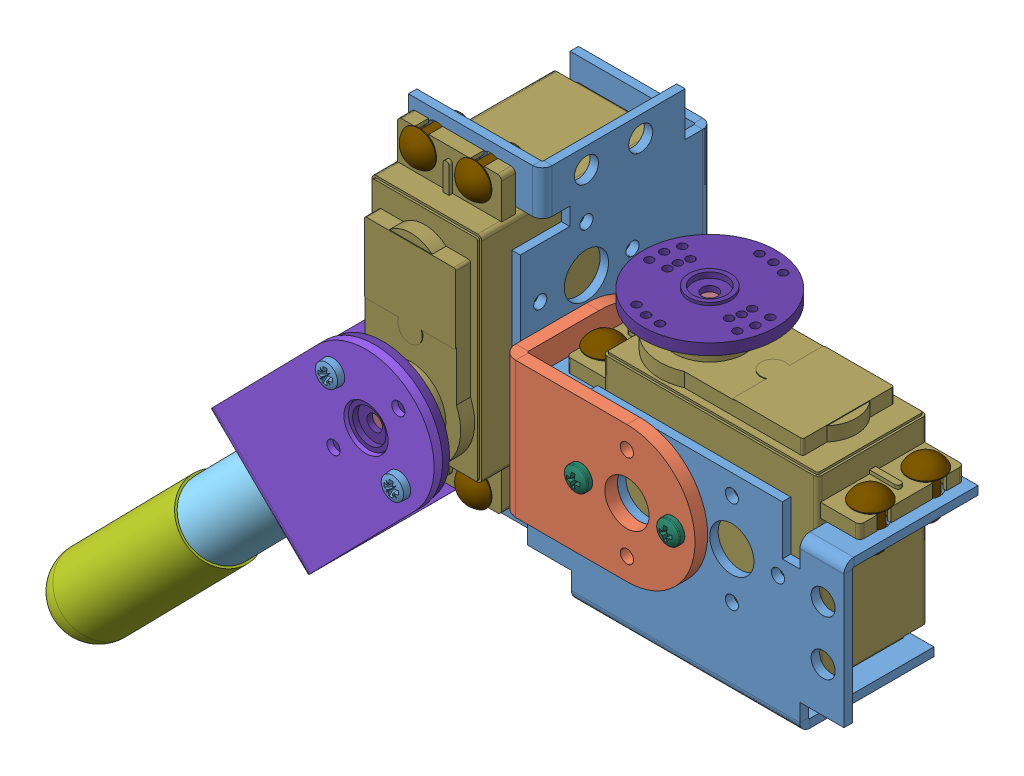
SolidWorks assembly 2DOFA, configuration Default. Lengths in mm.
Overall size (157.72 123.87 57.33).
51 component instances, 19 part files, 82 mates.
Components (placement in the parent):
- asb-04-1: asb-04 [Default] at (0 17.3609 0) x (-1 0 0) z (0 -1 0) size (57.15 24.21 34.72)
- asb-06-1: asb-06 [Default] at (-30.9626 22.7838 2.286) x (-1 0 0) z (0 -1 0) size (34.92 27.61 24.59)
- asb-04-2: asb-04 [Default] at (-30.9626 31.115 -18.4531) x (0 -1 0) z (0 0 -1) size (57.15 24.21 34.72)
- Nut Hex 2-56 (SN-02)-1: Nut Hex 2-56 (SN-02) [Default] at (-16.6624 22.7838 -3.2004) x (0.923728 0.383049 0) z (0 0 -1) size (4.78 5.51 1.68)
- Nut Hex 2-56 (SN-02)-2: Nut Hex 2-56 (SN-02) [Default] at (0 22.7838 -3.2004) x (0.923728 0.383049 0) z (0 0 -1) size (4.78 5.51 1.68)
- BB-03-1: BB-03 [Default] at (-7.842 -10.251 -1.0597) x (0 1 0) z (-0.297391 0 0.954756) size (4 9.5 9.5) (hidden)
- Nut Hex M3-1: Nut Hex M3 [Default] at (-9.9314 4.424 -14.2748) x (1 0 0) z (0 1 0) size (5.5 6.35 2.9)
- at-02-1: at-02 [Default] at (-66.3584 -0.3496 -13.6275) x (-0.713907 0.700241 0) z (-0.700241 -0.713907 0) size (12.7 12.7 76.2)
- 4-40 x 0.250 SHCS (SHS-01)-1: 4-40 x 0.250 SHCS (SHS-01) [Default] at (-73.0282 -7.1496 -22.8223) x (0 0 1) z (0.827472 -0.561508 0) size (9.19 4.65 4.65)
- REC-06-1: REC-06 [Default] at (-97.662 -32.2641 -13.6275) x (-0.713907 0.700241 0) z (0 0 1) size (13.46 38.1 13.46)
- asb-09-1: asb-09 [Default] at (-65.2468 0.7837 -13.6275) x (0 0 1) z (-0.713907 0.700241 0) size (52.25 40.87 24.61)
- BB-03-2: BB-03 [Default] at (-45.2374 21.1836 -40.6014) x (0 0 -1) z (0.990627 0.136598 0) size (4 9.5 9.5)
- hub-08-1: hub-08 [Default] at (-64.1352 1.917 -13.6275) x (0 0 1) z (0.713907 -0.700241 0) size (23.8 16.66 23.8)
- Washer Lock M3-1: Washer Lock M3 [Default] at (-45.2374 21.1836 -36.6014) x (0 0 -1) z (1 0 0) size (0.79 5.99 5.99)
- Nut Hex 2-56 (SN-02)-3: Nut Hex 2-56 (SN-02) [Default] at (-45.2374 21.1836 -32.6136) size (4.78 5.51 1.68)
- Nut Hex 2-56 (SN-02)-4: Nut Hex 2-56 (SN-02) [Default] at (-63.0057 3.0685 -21.9587) x (0.035595 -0.034914 -0.998756) z (0.700241 0.713907 0) size (4.78 5.51 1.68)
- Nut Hex 2-56 (SN-02)-5: Nut Hex 2-56 (SN-02) [Default] at (-63.0057 3.0685 -5.2963) x (0.035595 -0.034914 -0.998756) z (0.700241 0.713907 0) size (4.78 5.51 1.68)
- Servo_complete-1: Servo_complete [Default] at (0.0686 29.058 -14.2748) x (-1 0 0) z (0 0 -1) size (53 41.78 19.8)
  - Servo_case-1: Servo_case [Default] at origin size (53 38.29 19.8)
  - Output_shaft-1: Output_shaft [Default] at (10 3.0362 0) size (5.71 7.87 5.71)
  - Binding Head Screw_AI-1: Binding Head Screw_AI [CR-BHMS 0.06-80x0.625x0.625-S] at (-17.241 -25.1288 7.741) x (0 1 0) z (0 0 1) size (31.27 3.2 3.2)
  - Binding Head Screw_AI-2: Binding Head Screw_AI [CR-BHMS 0.06-80x0.625x0.625-S] at (-17.241 -25.1288 -7.741) x (0 1 0) z (0 0 1) size (31.27 3.2 3.2)
  - Binding Head Screw_AI-3: Binding Head Screw_AI [CR-BHMS 0.06-80x0.625x0.625-S] at (17.241 -25.1288 7.741) x (0 1 0) z (0 0 1) size (31.27 3.2 3.2)
  - Binding Head Screw_AI-4: Binding Head Screw_AI [CR-BHMS 0.06-80x0.625x0.625-S] at (17.241 -25.1288 -7.741) x (0 1 0) z (0 0 1) size (31.27 3.2 3.2)
- Servo_complete-2: Servo_complete [Default] at (-45.2374 31.1836 -6.756) x (0 -1 0) z (-1 0 0) size (53 41.78 19.8)
  - Servo_case-1: Servo_case [Default] at origin size (53 38.29 19.8)
  - Output_shaft-1: Output_shaft [Default] at (10 3.0362 0) size (5.71 7.87 5.71)
  - Binding Head Screw_AI-1: Binding Head Screw_AI [CR-BHMS 0.06-80x0.625x0.625-S] at (-17.241 -25.1288 7.741) x (0 1 0) z (0 0 1) size (31.27 3.2 3.2)
  - Binding Head Screw_AI-2: Binding Head Screw_AI [CR-BHMS 0.06-80x0.625x0.625-S] at (-17.241 -25.1288 -7.741) x (0 1 0) z (0 0 1) size (31.27 3.2 3.2)
  - Binding Head Screw_AI-3: Binding Head Screw_AI [CR-BHMS 0.06-80x0.625x0.625-S] at (17.241 -25.1288 7.741) x (0 1 0) z (0 0 1) size (31.27 3.2 3.2)
  - Binding Head Screw_AI-4: Binding Head Screw_AI [CR-BHMS 0.06-80x0.625x0.625-S] at (17.241 -25.1288 -7.741) x (0 1 0) z (0 0 1) size (31.27 3.2 3.2)
- 2-56 X 0.250 PHS (PHS-02)-5: 2-56 X 0.250 PHS (PHS-02) [Default] at (-16.6624 22.7838 3.8608) x (0 0 -1) z (1 0 0) size (7.89 4.24 4.24)
- 2-56 X 0.250 PHS (PHS-02)-6: 2-56 X 0.250 PHS (PHS-02) [Default] at (0 22.7838 3.8608) x (0 0 -1) z (1 0 0) size (7.89 4.24 4.24)
- Washer Lock M3-2: Washer Lock M3 [Default] at (-9.9314 0 -14.2748) x (0 1 0) z (0 0 1) size (0.79 5.99 5.99)
- BB-03-3: BB-03 [Default] at (-9.9314 -0.7874 -14.2748) x (0 1 0) z (-0.202028 0 0.97938) size (4 9.5 9.5)
- M3 X 8 LG PHMS (PHS-00)-1: M3 X 8 LG PHMS (PHS-00) [Default] at (-9.9314 -6.9874 -14.2748) x (0 1 0) z (0 0 1) size (10.37 5.6 5.6)
- 2-56 X 0.250 PHS (PHS-02)-7: 2-56 X 0.250 PHS (PHS-02) [Default] at (-67.4612 -1.4739 -21.9587) x (0.700241 0.713907 0) z (0 0 1) size (7.89 4.24 4.24)
- 2-56 X 0.250 PHS (PHS-02)-8: 2-56 X 0.250 PHS (PHS-02) [Default] at (-67.4612 -1.4739 -5.2963) x (0.700241 0.713907 0) z (0 0 1) size (7.89 4.24 4.24)
- M3 X 8 LG PHMS (PHS-00)-2: M3 X 8 LG PHMS (PHS-00) [Default] at (-45.2374 21.1836 -42.8014) x (0 0 1) z (-1 0 0) size (10.37 5.6 5.6)
- ServoHornPlastic-1: ServoHornPlastic [Default] at (-9.9314 47.234 -14.2748) x (0.986558 0 0.163414) z (-0.163414 0 0.986558) size (24 5 24)
- NSRF-01-1: NSRF-01 [Default] at (-23.9314 35.8273 -19.2748) x (0 -1 0) z (0 0 1) size (9.65 6.35 6.35)
- NSRF-01-2: NSRF-01 [Default] at (-23.9314 35.8273 -9.2748) x (0 -1 0) z (0 0 1) size (9.65 6.35 6.35)
- NSRF-01-3: NSRF-01 [Default] at (24.0686 35.8273 -9.2748) x (0 -1 0) z (0 0 1) size (9.65 6.35 6.35)
- NSRF-01-4: NSRF-01 [Default] at (24.0686 35.8273 -19.2748) x (0 -1 0) z (0 0 1) size (9.65 6.35 6.35)
- NSRF-01-6: NSRF-01 [Default] at (-40.2374 55.1836 0.0133) x (0 0 -1) z (1 0 0) size (9.65 6.35 6.35)
- NSRF-01-7: NSRF-01 [Default] at (-50.2374 55.1836 0.0133) x (0 0 -1) z (1 0 0) size (9.65 6.35 6.35)
- NSRF-01-8: NSRF-01 [Default] at (-40.2374 7.1836 0.0133) x (0 0 -1) z (1 0 0) size (9.65 6.35 6.35)
- NSRF-01-9: NSRF-01 [Default] at (-50.2374 7.1836 0.0133) x (0 0 -1) z (1 0 0) size (9.65 6.35 6.35)
- ServoHornPlastic-2: ServoHornPlastic [Default] at (-45.2374 21.1836 11.42) x (0.939703 -0.341991 0) z (-0.341991 -0.939703 0) size (24 5 24)
- #2 X 0.250 PHTS (PHTS-01)-1: #2 X 0.250 PHTS (PHTS-01) [Default] at (-39.2806 15.3409 12.4964) x (0 0 -1) z (1 0 0) size (6.96 5.97 5.51)
- #2 X 0.250 PHTS (PHTS-01)-2: #2 X 0.250 PHTS (PHTS-01) [Default] at (-51.1942 27.0263 12.4964) x (0 0 -1) z (1 0 0) size (6.96 5.97 5.51)
Mates (geometry in assembly coordinates):
- Coincident1: coincident anti-aligned: plane of asb-04-1 through (0 17.3609 0) normal (-1 0 0); plane of assembly
- Coincident2: coincident anti-aligned: plane of asb-04-1 through (52.1548 0 -1.524) normal (0 -1 0); plane of assembly
- Coincident3: coincident aligned: plane of asb-04-1 through (52.1548 17.3609 0) normal (0 0 1); plane of assembly
- Concentric1: concentric aligned: cylinder of asb-04-1; cylinder of asb-06-1
- Concentric2: concentric aligned: cylinder of asb-04-1; cylinder of asb-06-1
- Coincident4: coincident anti-aligned: plane of asb-04-1 through (52.1548 17.3609 0) normal (0 0 1); plane of asb-06-1 through (-8.3312 22.7838 0) normal (0 0 -1)
- Concentric3: concentric anti-aligned: cylinder of asb-06-1; cylinder of asb-04-2
- Coincident5: coincident anti-aligned: plane of asb-06-1 through (-30.9626 35.0774 0) normal (-1 0 0); plane of asb-04-2 through (-30.9626 83.2698 -18.4531) normal (1 0 0)
- Concentric141: concentric anti-aligned: cylinder of asb-04-1; cylinder of Nut Hex 2-56 (SN-02)-1
- Coincident151: coincident anti-aligned: plane of asb-04-1 through (52.1548 17.3609 -1.524) normal (0 0 -1); plane of Nut Hex 2-56 (SN-02)-1
- Concentric151: concentric anti-aligned: cylinder of asb-04-1; cylinder of Nut Hex 2-56 (SN-02)-2
- Coincident161: coincident anti-aligned: plane of asb-04-1 through (52.1548 17.3609 -1.524) normal (0 0 -1); plane of Nut Hex 2-56 (SN-02)-2
- Concentric221: concentric anti-aligned: cylinder of asb-04-1; cylinder of Nut Hex M3-1
- Coincident231: coincident anti-aligned: plane of asb-04-1 through (0 1.524 36.3136) normal (0 1 0); plane of Nut Hex M3-1
- Concentric2501: concentric aligned: cylinder of at-02-1; cylinder of 4-40 x 0.250 SHCS (SHS-01)-1
- Tangent1: tangent anti-aligned: cylinder of at-02-1; plane of 4-40 x 0.250 SHCS (SHS-01)-1
- Concentric2511: concentric aligned: cylinder of at-02-1; cylinder of REC-06-1
- Coincident2581: coincident anti-aligned: plane of at-02-1 through (-119.7168 -54.7493 0.4839) normal (-0.700241 -0.713907 0); plane of REC-06-1 through (-119.7168 -54.7493 -13.6275) normal (0.700241 0.713907 0)
- Concentric2513: concentric anti-aligned: cylinder of asb-06-1; cylinder of asb-04-2
- Concentric2518: concentric anti-aligned: cylinder of asb-09-1; cylinder of BB-03-2
- Coincident2585: coincident anti-aligned: plane of asb-09-1 through (-4.4574 -1.5956 -39.7514) normal (0 0 -1); plane of BB-03-2 through (-45.8862 25.8891 -39.7514) normal (0 0 1)
- Concentric25291: concentric anti-aligned: cylinder of asb-09-1; cylinder of hub-08-1
- Coincident25951: coincident anti-aligned: plane of asb-09-1 through (-33.0752 -30.772 -13.6275) normal (-0.700241 -0.713907 0); plane of hub-08-1 through (-80.8157 16.0546 -13.6275) normal (0.700241 0.713907 0)
- Concentric2530: concentric anti-aligned: cylinder of asb-09-1; cylinder of hub-08-1
- Concentric2531: concentric aligned: cylinder of at-02-1; cylinder of hub-08-1
- Concentric2532: concentric anti-aligned: cylinder of at-02-1; cylinder of hub-08-1
- Concentric25331: concentric anti-aligned: cylinder of BB-03-2; cylinder of Washer Lock M3-1
- Coincident25961: coincident anti-aligned: plane of BB-03-2 through (-45.5557 23.4918 -36.6014) normal (0 0 1); plane of Washer Lock M3-1
- Concentric2534: concentric anti-aligned: cylinder of asb-04-2; cylinder of asb-09-1
- Coincident2597: coincident anti-aligned: plane of asb-04-2 through (-32.4866 83.2698 -35.814) normal (0 0 -1); plane of Washer Lock M3-1
- Concentric25351: concentric anti-aligned: cylinder of asb-04-2; cylinder of Nut Hex 2-56 (SN-02)-3
- Coincident25981: coincident anti-aligned: plane of asb-04-2 through (5.351 31.115 -34.29) normal (0 0 1); plane of Nut Hex 2-56 (SN-02)-3
- Concentric25401: concentric anti-aligned: cylinder of asb-09-1; cylinder of Nut Hex 2-56 (SN-02)-4
- Coincident26031: coincident anti-aligned: plane of asb-09-1 through (-32.0081 -29.684 -13.6275) normal (0.700241 0.713907 0); plane of Nut Hex 2-56 (SN-02)-4
- Concentric25411: concentric anti-aligned: cylinder of asb-09-1; cylinder of Nut Hex 2-56 (SN-02)-5
- Coincident26041: coincident anti-aligned: plane of asb-09-1 through (-32.0081 -29.684 -13.6275) normal (0.700241 0.713907 0); plane of Nut Hex 2-56 (SN-02)-5
- Concentric2544: concentric aligned: cylinder of asb-04-1; cylinder of Servo_complete-1/Servo_case-1
- Coincident2607: coincident anti-aligned: plane of asb-04-1 through (52.1548 30.734 -1.524) normal (0 1 0); plane of Servo_complete-1/Servo_case-1 through (-26.4314 30.734 -23.6748) normal (0 -1 0)
- Parallel3: parallel aligned: plane of asb-04-1 through (0 -18.3812 -24.2062) normal (0 0 -1); plane of Servo_complete-1/Servo_case-1 through (26.5686 33.234 -23.6748) normal (0 0 -1)
- Concentric2545: concentric anti-aligned: cylinder of asb-09-1; cylinder of Servo_complete-2/Servo_case-1
- Coincident2608: coincident anti-aligned: plane of asb-04-2 through (-32.4866 83.2698 -5.08) normal (0 0 1); plane of Servo_complete-2/Servo_case-1 through (-54.6374 57.6836 -5.08) normal (0 0 -1)
- Parallel4: parallel aligned: plane of asb-04-2 through (-30.9626 83.2698 -18.4531) normal (1 0 0); plane of Servo_complete-2/Servo_case-1 through (-35.3374 49.8216 1.499) normal (1 0 0)
- Concentric254121: concentric aligned: cylinder of asb-06-1; cylinder of 2-56 X 0.250 PHS (PHS-02)-5
- Coincident260421: coincident anti-aligned: plane of asb-06-1 through (-8.3312 22.7838 2.286) normal (0 0 1); plane of 2-56 X 0.250 PHS (PHS-02)-5
- Concentric254131: concentric aligned: cylinder of asb-06-1; cylinder of 2-56 X 0.250 PHS (PHS-02)-6
- Coincident260431: coincident anti-aligned: plane of asb-06-1 through (-8.3312 22.7838 2.286) normal (0 0 1); plane of 2-56 X 0.250 PHS (PHS-02)-6
- Concentric254141: concentric aligned: cylinder of asb-04-1; cylinder of Washer Lock M3-2
- Coincident260441: coincident anti-aligned: plane of asb-04-1 through (52.1548 0 -1.524) normal (0 -1 0); plane of Washer Lock M3-2
- Concentric25415: concentric anti-aligned: cylinder of asb-04-1; cylinder of BB-03-3
- Coincident26045: coincident anti-aligned: plane of Washer Lock M3-2; plane of BB-03-3 through (-13.0311 -0.7874 -14.9142) normal (0 1 0)
- Concentric254161: concentric anti-aligned: cylinder of BB-03-3; cylinder of M3 X 8 LG PHMS (PHS-00)-1
- Coincident260461: coincident anti-aligned: plane of BB-03-3 through (-13.0311 -4.5874 -14.9142) normal (0 -1 0); plane of M3 X 8 LG PHMS (PHS-00)-1
- Concentric254171: concentric anti-aligned: cylinder of hub-08-1; cylinder of 2-56 X 0.250 PHS (PHS-02)-7
- Coincident260471: coincident anti-aligned: plane of hub-08-1 through (-81.9273 14.9212 -13.6275) normal (-0.700241 -0.713907 0); plane of 2-56 X 0.250 PHS (PHS-02)-7
- Concentric254181: concentric anti-aligned: cylinder of hub-08-1; cylinder of 2-56 X 0.250 PHS (PHS-02)-8
- Coincident260481: coincident anti-aligned: plane of hub-08-1 through (-81.9273 14.9212 -13.6275) normal (-0.700241 -0.713907 0); plane of 2-56 X 0.250 PHS (PHS-02)-8
- Concentric254191: concentric aligned: cylinder of BB-03-2; cylinder of M3 X 8 LG PHMS (PHS-00)-2
- Coincident260491: coincident anti-aligned: plane of BB-03-2 through (-45.6697 24.3189 -40.4014) normal (0 0 -1); plane of M3 X 8 LG PHMS (PHS-00)-2
- Concentric25421: concentric anti-aligned: cylinder of Servo_complete-1/Servo_case-1; cylinder of ServoHornPlastic-1
- Coincident26051: coincident anti-aligned: plane of Servo_complete-1/Output_shaft-1 through (-12.7889 45.734 -14.2748) normal (0 1 0); plane of ServoHornPlastic-1 through (-9.9314 45.734 -14.2748) normal (0 -1 0)
- Concentric254221: concentric aligned: cylinder of Servo_complete-1/Servo_case-1; cylinder of NSRF-01-1
- Coincident260521: coincident anti-aligned: plane of Servo_complete-1/Servo_case-1 through (-26.4314 33.234 -23.6748) normal (0 1 0); plane of NSRF-01-1 through (-22.6536 33.234 -19.2748) normal (0 -1 0)
- Concentric254231: concentric aligned: cylinder of Servo_complete-1/Servo_case-1; cylinder of NSRF-01-2
- Coincident260531: coincident anti-aligned: plane of Servo_complete-1/Servo_case-1 through (-26.4314 33.234 -23.6748) normal (0 1 0); plane of NSRF-01-2 through (-22.6536 33.234 -9.2748) normal (0 -1 0)
- Concentric254241: concentric aligned: cylinder of Servo_complete-1/Servo_case-1; cylinder of NSRF-01-3
- Coincident260541: coincident anti-aligned: plane of Servo_complete-1/Servo_case-1 through (26.5686 33.234 -23.6748) normal (0 1 0); plane of NSRF-01-3 through (25.3464 33.234 -9.2748) normal (0 -1 0)
- Concentric254251: concentric aligned: cylinder of Servo_complete-1/Servo_case-1; cylinder of NSRF-01-4
- Coincident260551: coincident anti-aligned: plane of Servo_complete-1/Servo_case-1 through (26.5686 33.234 -23.6748) normal (0 1 0); plane of NSRF-01-4 through (25.3464 33.234 -19.2748) normal (0 -1 0)
- Concentric254271: concentric aligned: cylinder of Servo_complete-2/Servo_case-1; cylinder of NSRF-01-6
- Coincident260571: coincident anti-aligned: plane of Servo_complete-2/Servo_case-1 through (-54.6374 57.6836 -2.58) normal (0 0 1); plane of NSRF-01-6 through (-40.2374 56.4614 -2.58) normal (0 0 -1)
- Concentric254281: concentric aligned: cylinder of Servo_complete-2/Servo_case-1; cylinder of NSRF-01-7
- Coincident260581: coincident anti-aligned: plane of Servo_complete-2/Servo_case-1 through (-54.6374 57.6836 -2.58) normal (0 0 1); plane of NSRF-01-7 through (-50.2374 56.4614 -2.58) normal (0 0 -1)
- Concentric254291: concentric aligned: cylinder of Servo_complete-2/Servo_case-1; cylinder of NSRF-01-8
- Coincident260591: coincident anti-aligned: plane of Servo_complete-2/Servo_case-1 through (-54.6374 4.6836 -2.58) normal (0 0 1); plane of NSRF-01-8 through (-40.2374 8.4614 -2.58) normal (0 0 -1)
- Concentric254301: concentric aligned: cylinder of Servo_complete-2/Servo_case-1; cylinder of NSRF-01-9
- Coincident260601: coincident anti-aligned: plane of Servo_complete-2/Servo_case-1 through (-54.6374 4.6836 -2.58) normal (0 0 1); plane of NSRF-01-9 through (-50.2374 8.4614 -2.58) normal (0 0 -1)
- Concentric25431: concentric anti-aligned: cylinder of Servo_complete-2/Servo_case-1; cylinder of ServoHornPlastic-2
- Coincident26061: coincident anti-aligned: plane of Servo_complete-2/Output_shaft-1 through (-45.2374 18.3261 9.92) normal (0 0 1); plane of ServoHornPlastic-2 through (-45.2374 21.1836 9.92) normal (0 0 -1)
- Concentric254321: concentric anti-aligned: cylinder of asb-09-1; cylinder of #2 X 0.250 PHTS (PHTS-01)-1
- Coincident260621: coincident anti-aligned: plane of asb-09-1 through (-4.4574 -1.5956 12.4964) normal (0 0 1); plane of #2 X 0.250 PHTS (PHTS-01)-1 through (-39.2806 16.9474 12.4964) normal (0 0 -1)
- Concentric254331: concentric anti-aligned: cylinder of asb-09-1; cylinder of #2 X 0.250 PHTS (PHTS-01)-2
- Coincident260631: coincident anti-aligned: plane of asb-09-1 through (-4.4574 -1.5956 12.4964) normal (0 0 1); plane of #2 X 0.250 PHTS (PHTS-01)-2 through (-51.1942 28.6329 12.4964) normal (0 0 -1)
